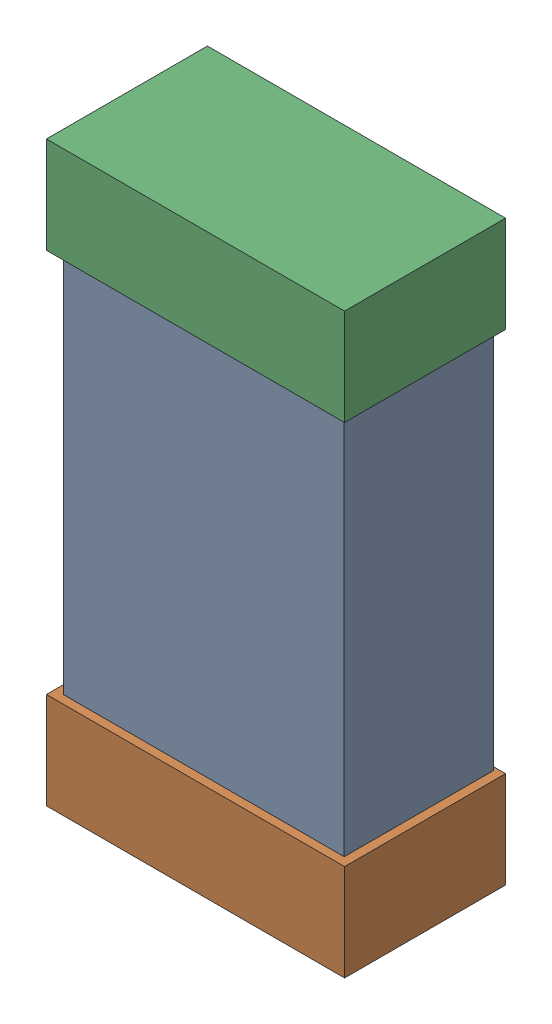
SolidWorks assembly R8, configuration Default. Lengths in mm.
Overall size (0.85 1.65 0.46).
6 component instances, 2 part files, 0 mates.
Components (placement in the parent):
- 432124816_47-1: 432124816_47 [Default] at (33.4001 24.9001 -0.8615) size (0.8 1.5 0.42)
  - Extruded (1)-1: Extruded (1) [Default] at origin size (0.8 1.5 0.42)
- 432138512_94-1: 432138512_94 [Default] at (33.4001 24.2143 -0.8715) size (0.85 0.28 0.46)
  - Extruded-1: Extruded [Default] at origin size (0.85 0.28 0.46)
- 432138512_95-1: 432138512_95 [Default] at (33.4001 25.5859 -0.8715) size (0.85 0.28 0.46)
  - Extruded-1: Extruded [Default] at origin size (0.85 0.28 0.46)
